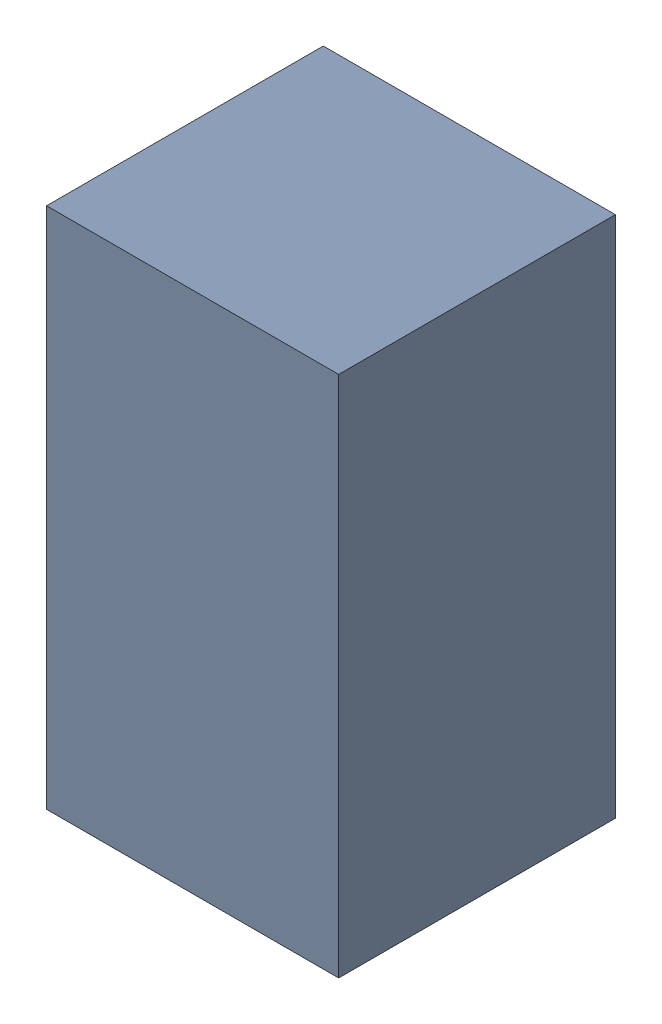
SolidWorks assembly R1, configuration Default. Lengths in mm.
Overall size (0.95 1.7 0.9).
2 component instances, 1 part files, 0 mates.
Components (placement in the parent):
- 4438511040-1: 4438511040 [Default] at (11.442 10.656 0) size (0.95 1.7 0.9)
  - Extruded_2-1: Extruded_2 [Default] at origin size (0.95 1.7 0.9)
